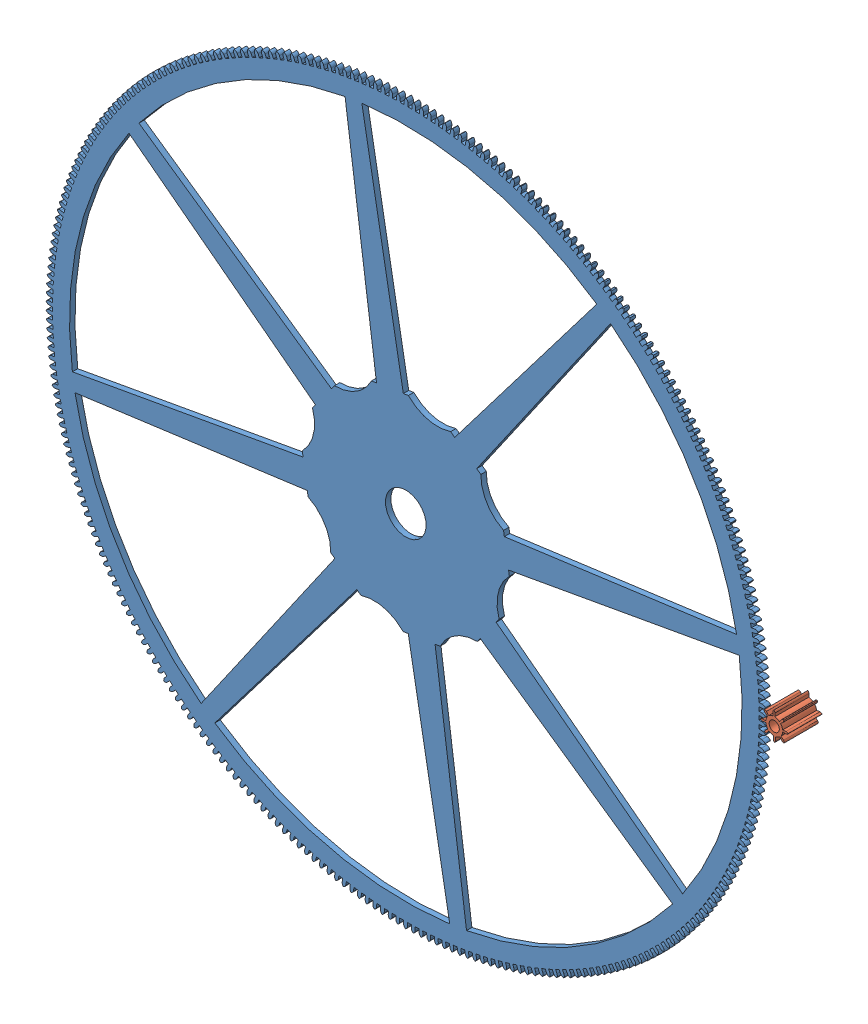
SolidWorks assembly depthing, configuration Default. Lengths in mm.
Overall size (296.01 296.01 10).
2 component instances, 2 part files, 5 mates.
Components (placement in the parent):
- great wheel-1: great wheel [Default] at (-118.09 -87.7309 0) x (-0.808579 0.588387 0) z (0 0 1) size (211.89 211.9 1.59)
- pinon-1: pinon [Default] at (54.25 0 0) x (0.727266 -0.686356 0) z (0 0 1) size (8.11 8.11 10)
Mates (geometry in assembly coordinates):
- Coincident2: coincident: plane of great wheel-1 through (-54.25 0 0) normal (0 0 1); plane of assembly
- Concentric1: concentric: circle of great wheel-1; circle of assembly
- Coincident3: coincident: plane of great wheel-1 through (-54.25 0 0) normal (0 0 1); plane of pinon-1 through (56.4015 2.7606 0) normal (0 0 1)
- Concentric2: concentric: circle of pinon-1; circle of assembly
- GearMate2: gear = 8 : 290 mm: circle of great wheel-1; circle of pinon-1
